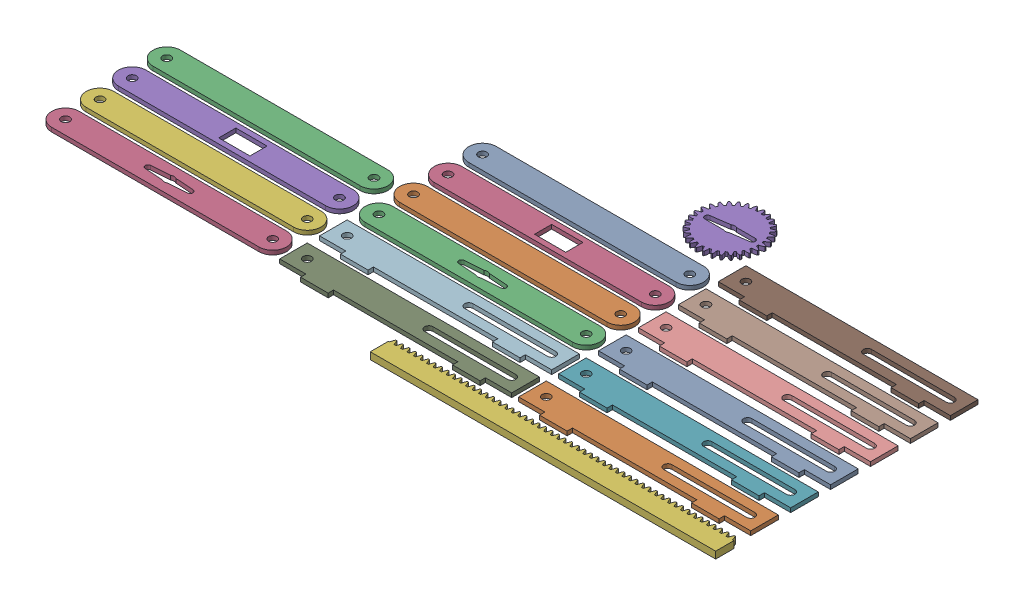
SolidWorks assembly Acryllic Parts, configuration Default. Lengths in mm.
Overall size (517.69 5 232.93).
18 component instances, 6 part files, 49 mates.
Components (placement in the parent):
- Lift Arm-1: Lift Arm [Default] at (22.6825 223.8354 126.7114) x (-1 0 0) z (0 -1 0) size (170 20 3)
- Lift Arm-2: Lift Arm [Default] at (22.6825 223.8354 176.7114) x (-1 0 0) z (0 -1 0) size (170 20 3)
- Servo Lift Arm - Inner-1: Servo Lift Arm - Inner [Default] at (22.6825 223.8354 201.7114) x (-1 0 0) z (0 -1 0) size (170 20 3)
- Servo Lift Arm - Outer-1: Servo Lift Arm - Outer [Default] at (22.6825 223.8354 151.7114) x (-1 0 0) z (0 -1 0) size (170 20 3)
- Servo Gear-5: Servo Gear [Servo] at (83.6825 220.8354 83.6355) x (0 1 0) z (-0.997492 0 0.070784) size (3 47.82 48)
- rack spur rectangular_am-2: rack spur rectangular_am [Metric - Rack-spur - rectangular 1.5M 20PA 5FW 15PH 250L---SAll] at (30.6825 223.8354 291.0114) x (1 0 0) z (0 1 0) size (250 16.5 5)
- Lift Axle Track-1: Lift Axle Track [Default] at (112.6825 220.8354 236.7114) size (168 3 23.9)
- Lift Axle Track-2: Lift Axle Track [Default] at (112.6825 220.8354 150.0114) size (168 3 23.9)
- Lift Axle Track-3: Lift Axle Track [Default] at (-60.3175 220.8354 265.6114) size (168 3 23.9)
- Lift Axle Track-4: Lift Axle Track [Default] at (112.6825 220.8354 178.9114) size (168 3 23.9)
- Lift Axle Track-5: Lift Axle Track [Default] at (112.6825 220.8354 121.1114) size (168 3 23.9)
- Lift Axle Track-6: Lift Axle Track [Default] at (-60.3175 220.8354 236.7114) size (168 3 23.9)
- Lift Axle Track-7: Lift Axle Track [Default] at (112.6825 220.8354 207.8114) size (168 3 23.9)
- Lift Axle Track-8: Lift Axle Track [Default] at (112.6825 220.8354 265.6114) size (168 3 23.9)
- Lift Arm-3: Lift Arm [Default] at (-152.0114 223.8354 180.6114) x (-1 0 0) z (0 -1 0) size (170 20 3)
- Servo Lift Arm - Inner-2: Servo Lift Arm - Inner [Default] at (-150.3175 223.8354 255.6114) x (-1 0 0) z (0 -1 0) size (170 20 3)
- Servo Lift Arm - Outer-2: Servo Lift Arm - Outer [Default] at (-152.0114 223.8354 205.6114) x (-1 0 0) z (0 -1 0) size (170 20 3)
- Lift Arm-4: Lift Arm [Default] at (-150.3175 223.8354 230.6114) x (-1 0 0) z (0 -1 0) size (170 20 3)
Mates (geometry in assembly coordinates):
- Coincident1: coincident aligned: plane of Servo Gear-5 through (83.6825 223.8354 83.6355) normal (0 1 0); plane of Lift Axle Track-5 through (112.6825 223.8354 121.1114) normal (0 1 0)
- Coincident2: coincident aligned: plane of Servo Gear-5 through (83.6825 223.8354 83.6355) normal (0 1 0); plane of Lift Axle Track-4 through (112.6825 223.8354 178.9114) normal (0 1 0)
- Coincident3: coincident aligned: plane of Servo Gear-5 through (83.6825 223.8354 83.6355) normal (0 1 0); plane of Lift Axle Track-1 through (112.6825 223.8354 236.7114) normal (0 1 0)
- Coincident4: coincident aligned: plane of Servo Gear-5 through (83.6825 223.8354 83.6355) normal (0 1 0); plane of Lift Axle Track-6 through (-60.3175 223.8354 236.7114) normal (0 1 0)
- Coincident5: coincident aligned: plane of Servo Gear-5 through (83.6825 223.8354 83.6355) normal (0 1 0); plane of Lift Axle Track-7 through (112.6825 223.8354 207.8114) normal (0 1 0)
- Coincident6: coincident aligned: plane of Servo Gear-5 through (83.6825 223.8354 83.6355) normal (0 1 0); plane of Lift Axle Track-8 through (112.6825 223.8354 265.6114) normal (0 1 0)
- Coincident7: coincident aligned: plane of Servo Gear-5 through (83.6825 223.8354 83.6355) normal (0 1 0); plane of Lift Axle Track-3 through (-60.3175 223.8354 265.6114) normal (0 1 0)
- Coincident8: coincident aligned: plane of Servo Gear-5 through (83.6825 223.8354 83.6355) normal (0 1 0); plane of Lift Axle Track-2 through (112.6825 223.8354 150.0114) normal (0 1 0)
- Coincident10: coincident aligned: plane of Servo Lift Arm - Inner-1 through (-52.3175 223.8354 201.7114) normal (0 1 0); plane of Servo Gear-5 through (83.6825 223.8354 83.6355) normal (0 1 0)
- Coincident11: coincident aligned: plane of Servo Lift Arm - Outer-1 through (-52.3175 223.8354 151.7114) normal (0 1 0); plane of Servo Gear-5 through (83.6825 223.8354 83.6355) normal (0 1 0)
- Distance1: distance = 5 mm anti-aligned: plane of Lift Axle Track-8 through (261.6825 223.8354 269.5114) normal (0 0 1); plane of Spur Rack-2 through (30.6825 218.8354 274.5114) normal (0 0 -1)
- Distance2: distance = 5 mm anti-aligned: plane of Lift Axle Track-1 through (131.6825 223.8354 240.6114) normal (0 0 1); plane of Lift Axle Track-8 through (112.6825 223.8354 245.6114) normal (0 0 -1)
- Distance3: distance = 5 mm anti-aligned: plane of Lift Axle Track-7 through (131.6825 223.8354 211.7114) normal (0 0 1); plane of Lift Axle Track-1 through (112.6825 223.8354 216.7114) normal (0 0 -1)
- Distance4: distance = 5 mm anti-aligned: plane of Lift Axle Track-4 through (131.6825 223.8354 182.8114) normal (0 0 1); plane of Lift Axle Track-7 through (112.6825 223.8354 187.8114) normal (0 0 -1)
- Coincident19: coincident aligned: plane of Spur Rack-2 through (280.6825 218.8354 291.0114) normal (1 0 0); plane of Lift Axle Track-8 through (280.6825 223.8354 265.6114) normal (1 0 0)
- Coincident20: coincident aligned: plane of Spur Rack-2 through (280.6825 218.8354 291.0114) normal (1 0 0); plane of Lift Axle Track-1 through (280.6825 223.8354 236.7114) normal (1 0 0)
- Coincident21: coincident aligned: plane of Spur Rack-2 through (280.6825 218.8354 291.0114) normal (1 0 0); plane of Lift Axle Track-7 through (280.6825 223.8354 207.8114) normal (1 0 0)
- Coincident22: coincident aligned: plane of Spur Rack-2 through (280.6825 218.8354 291.0114) normal (1 0 0); plane of Lift Axle Track-4 through (280.6825 223.8354 178.9114) normal (1 0 0)
- Distance5: distance = 5 mm anti-aligned: plane of Lift Axle Track-3 through (88.6825 223.8354 269.5114) normal (0 0 1); plane of Spur Rack-2 through (30.6825 218.8354 274.5114) normal (0 0 -1)
- Distance6: distance = 5 mm anti-aligned: plane of Lift Axle Track-6 through (88.6825 223.8354 240.6114) normal (0 0 1); plane of Lift Axle Track-3 through (-60.3175 223.8354 245.6114) normal (0 0 -1)
- Distance7: distance = 5 mm anti-aligned: plane of Servo Lift Arm - Inner-1 through (-52.3175 220.8354 211.7114) normal (0 0 1); plane of Lift Axle Track-6 through (-60.3175 223.8354 216.7114) normal (0 0 -1)
- Distance8: distance = 5 mm anti-aligned: plane of Lift Arm-2 through (22.6825 220.8354 186.7114) normal (0 0 1); plane of Servo Lift Arm - Inner-1 through (-52.3175 220.8354 191.7114) normal (0 0 -1)
- Coincident27: coincident aligned: plane of Lift Axle Track-3 through (107.6825 223.8354 265.6114) normal (1 0 0); plane of Lift Axle Track-6 through (107.6825 223.8354 236.7114) normal (1 0 0)
- Distance9: distance = 5 mm anti-aligned: plane of Servo Lift Arm - Outer-1 through (-52.3175 220.8354 161.7114) normal (0 0 1); plane of Lift Arm-2 through (22.6825 220.8354 166.7114) normal (0 0 -1)
- Distance10: distance = 5 mm anti-aligned: plane of Servo Lift Arm - Outer-1 through (-52.3175 220.8354 141.7114) normal (0 0 -1); plane of Lift Arm-1 through (22.6825 220.8354 136.7114) normal (0 0 1)
- Tangent1: tangent aligned: cylinder of Servo Lift Arm - Inner-1 through (97.6825 220.8354 201.7114) axis (0 1 0) radius 10; plane of Lift Axle Track-6 through (107.6825 223.8354 236.7114) normal (1 0 0)
- Tangent2: tangent aligned: cylinder of Lift Arm-2 through (97.6825 220.8354 176.7114) axis (0 1 0) radius 10; plane of Lift Axle Track-6 through (107.6825 223.8354 236.7114) normal (1 0 0)
- Tangent3: tangent aligned: cylinder of Servo Lift Arm - Outer-1 through (97.6825 220.8354 151.7114) axis (0 1 0) radius 10; plane of Lift Axle Track-6 through (107.6825 223.8354 236.7114) normal (1 0 0)
- Tangent4: tangent aligned: cylinder of Lift Arm-1 through (97.6825 220.8354 126.7114) axis (0 1 0) radius 10; plane of Lift Axle Track-6 through (107.6825 223.8354 236.7114) normal (1 0 0)
- Distance11: distance = 5 mm anti-aligned: plane of Lift Axle Track-4 through (112.6825 223.8354 158.9114) normal (0 0 -1); plane of Lift Axle Track-2 through (261.6825 223.8354 153.9114) normal (0 0 1)
- Coincident31: coincident aligned: plane of Spur Rack-2 through (30.6825 223.8354 274.5114) normal (0 1 0); plane of Lift Axle Track-8 through (112.6825 223.8354 265.6114) normal (0 1 0)
- Distance13: distance = 5 mm anti-aligned: plane of Lift Axle Track-5 through (261.6825 223.8354 125.0114) normal (0 0 1); plane of Lift Axle Track-2 through (112.6825 223.8354 130.0114) normal (0 0 -1)
- Coincident33: coincident aligned: plane of Lift Axle Track-2 through (280.6825 223.8354 150.0114) normal (1 0 0); plane of Lift Axle Track-4 through (280.6825 223.8354 178.9114) normal (1 0 0)
- Coincident34: coincident aligned: plane of Lift Axle Track-2 through (280.6825 223.8354 150.0114) normal (1 0 0); plane of Lift Axle Track-5 through (280.6825 223.8354 121.1114) normal (1 0 0)
- Distance14: distance = 5 mm anti-aligned: plane of Lift Axle Track-6 through (107.6825 223.8354 236.7114) normal (1 0 0); plane of Lift Axle Track-1 through (112.6825 223.8354 236.7114) normal (-1 0 0)
- Distance15: distance = 30 mm aligned: plane of Lift Arm-1 through (22.6825 220.8354 116.7114) normal (0 0 -1); plane of Servo Gear-5 through (68.5207 223.8354 86.7114) normal (0 0 -1)
- Tangent5: tangent aligned: cylinder of Servo Gear-5 through (83.6825 210.8354 83.6355) axis (0 -1 0) radius 24; plane of Lift Axle Track-3 through (107.6825 223.8354 265.6114) normal (1 0 0)
- Distance16: distance = 5 mm anti-aligned: plane of Servo Lift Arm - Outer-2 through (-227.0114 220.8354 195.6114) normal (0 0 -1); plane of Lift Arm-3 through (-152.0114 220.8354 190.6114) normal (0 0 1)
- Distance17: distance = 5 mm anti-aligned: plane of Servo Lift Arm - Outer-2 through (-227.0114 220.8354 215.6114) normal (0 0 1); plane of Lift Arm-4 through (-150.3175 220.8354 220.6114) normal (0 0 -1)
- Distance18: distance = 5 mm anti-aligned: plane of Lift Arm-4 through (-150.3175 220.8354 240.6114) normal (0 0 1); plane of Servo Lift Arm - Inner-2 through (-225.3175 220.8354 245.6114) normal (0 0 -1)
- Coincident35: coincident aligned: plane of Lift Axle Track-3 through (-60.3175 223.8354 265.6114) normal (0 0 1); plane of Servo Lift Arm - Inner-2 through (-225.3175 220.8354 265.6114) normal (0 0 1)
- Coincident37: coincident aligned: plane of Lift Arm-3 through (-239.5947 223.8354 180.6114) normal (0 1 0); plane of Servo Lift Arm - Outer-2 through (-227.0114 223.8354 205.6114) normal (0 1 0)
- Coincident38: coincident aligned: plane of Lift Arm-3 through (-239.5947 223.8354 180.6114) normal (0 1 0); plane of Lift Arm-4 through (-150.3175 223.8354 230.6114) normal (0 1 0)
- Coincident39: coincident aligned: plane of Lift Arm-3 through (-239.5947 223.8354 180.6114) normal (0 1 0); plane of Servo Lift Arm - Inner-2 through (-225.3175 223.8354 255.6114) normal (0 1 0)
- Coincident40: coincident aligned: plane of Lift Axle Track-6 through (-60.3175 223.8354 236.7114) normal (0 1 0); plane of Lift Arm-3 through (-239.5947 223.8354 180.6114) normal (0 1 0)
- Distance20: distance = 5 mm anti-aligned: plane of Lift Axle Track-3 through (-60.3175 223.8354 265.6114) normal (-1 0 0); cylinder of Servo Lift Arm - Inner-2 through (-75.3175 220.8354 255.6114) axis (0 1 0) radius 10
- Distance21: distance = 5 mm anti-aligned: cylinder of Lift Arm-4 through (-75.3175 220.8354 230.6114) axis (0 1 0) radius 10; plane of Lift Axle Track-6 through (-60.3175 223.8354 236.7114) normal (-1 0 0)
- Distance22: distance = 5 mm: cylinder of Servo Lift Arm - Outer-2 through (-77.0114 220.8354 205.6114) axis (0 1 0) radius 10; cylinder of Servo Lift Arm - Inner-1 through (-52.3175 220.8354 201.7114) axis (0 1 0) radius 10
- Distance23: distance = 5 mm: cylinder of Lift Arm-3 through (-77.0114 220.8354 180.6114) axis (0 1 0) radius 10; cylinder of Lift Arm-2 through (-52.3175 220.8354 176.7114) axis (0 1 0) radius 10
